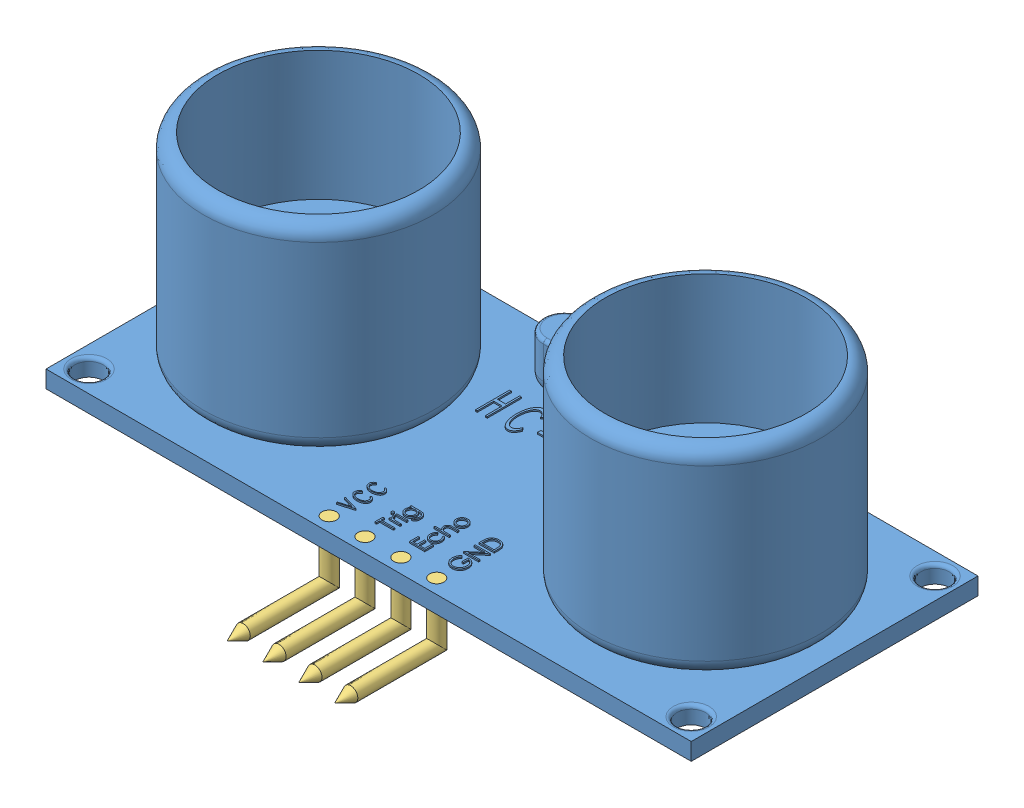
SolidWorks assembly Assem3, configuration Default. Lengths in mm.
Overall size (45 18.3 26.12).
7 component instances, 3 part files, 15 mates.
Components (placement in the parent):
- UltraSonic-1: UltraSonic [Default] at (-2.8609 -7.9267 1.7996) size (45 15 20)
- part2-1: part2 [Default] at (10.6391 -2.6926 1.7996) x (0.988186 0 -0.153259) z (0.153259 0 0.988186) size (8 0.63 8)
- part2-2: part2 [Default] at (-16.3609 -2.9267 1.7996) x (0.862539 0 -0.505991) z (0.505991 0 0.862539) size (8 0.63 8)
- pin header-1: pin header [Default] at (-6.6109 -10.7267 50.9724) x (0 0 -1) z (1 0 0) size (7.62 4.5 1)
- pin header-2: pin header [Default] at (-4.1109 -10.7267 50.9724) x (0 0 -1) z (1 0 0) size (7.62 4.5 1)
- pin header-3: pin header [Default] at (0.8891 -10.7267 50.9724) x (0 0 -1) z (1 0 0) size (7.62 4.5 1)
- pin header-4: pin header [Default] at (-1.6109 -10.7267 50.9724) x (0 0 -1) z (1 0 0) size (7.62 4.5 1)
Mates (geometry in assembly coordinates):
- Coincident3: coincident: circle of UltraSonic-1; cone of part2-1 through (10.6391 -2.0627 1.7996) axis (0 -1 0)
- Concentric7: concentric aligned: circle of UltraSonic-1; circle of part2-2
- Coincident4: coincident aligned: plane of UltraSonic-1 through (-16.3609 -2.9267 1.7996) normal (0 1 0); circle of part2-2
- Concentric8: concentric aligned: cylinder of UltraSonic-1 through (-6.6109 -7.9267 10.7996) axis (0 1 0) radius 0.5; cylinder of pin header-1 through (-6.6109 -12.141 10.7996) axis (0 1 0) radius 0.5
- Coincident5: coincident aligned: plane of UltraSonic-1 through (19.6391 -6.7267 11.7996) normal (0 1 0); plane of pin header-1 through (-6.6109 -6.7267 10.7996) normal (0 1 0)
- Coincident6: coincident aligned: circle of UltraSonic-1; cylinder of pin header-2 through (-4.1109 -12.141 10.7996) axis (0 1 0) radius 0.5
- Coincident7: coincident aligned: plane of UltraSonic-1 through (19.6391 -6.7267 11.7996) normal (0 1 0); plane of pin header-2 through (-4.1109 -6.7267 10.7996) normal (0 1 0)
- Concentric9: concentric aligned: cylinder of UltraSonic-1 through (-1.6109 -7.9267 10.7996) axis (0 1 0) radius 0.5; cylinder of pin header-4 through (-1.6109 -12.141 10.7996) axis (0 1 0) radius 0.5
- Coincident8: coincident aligned: plane of UltraSonic-1 through (19.6391 -6.7267 11.7996) normal (0 1 0); plane of pin header-4 through (-1.6109 -6.7267 10.7996) normal (0 1 0)
- Concentric10: concentric aligned: cylinder of UltraSonic-1 through (0.8891 -7.9267 10.7996) axis (0 1 0) radius 0.5; cylinder of pin header-3 through (0.8891 -12.141 10.7996) axis (0 1 0) radius 0.5
- Coincident9: coincident aligned: plane of UltraSonic-1 through (19.6391 -6.7267 11.7996) normal (0 1 0); plane of pin header-3 through (0.8891 -6.7267 10.7996) normal (0 1 0)
- Parallel8: parallel anti-aligned: line of UltraSonic-1 through (19.6391 -6.7267 11.7996) axis (0 0 -1); cylinder of pin header-3 through (0.8891 -10.7267 10.7996) axis (0 0 1) radius 0.5
- Parallel9: parallel anti-aligned: line of UltraSonic-1 through (19.6391 -6.7267 11.7996) axis (0 0 -1); cylinder of pin header-4 through (-1.6109 -10.7267 10.7996) axis (0 0 1) radius 0.5
- Parallel10: parallel anti-aligned: line of UltraSonic-1 through (19.6391 -6.7267 11.7996) axis (0 0 -1); cylinder of pin header-2 through (-4.1109 -10.7267 10.7996) axis (0 0 1) radius 0.5
- Parallel11: parallel anti-aligned: line of UltraSonic-1 through (19.6391 -6.7267 11.7996) axis (0 0 -1); cylinder of pin header-1 through (-6.6109 -10.7267 10.7996) axis (0 0 1) radius 0.5
